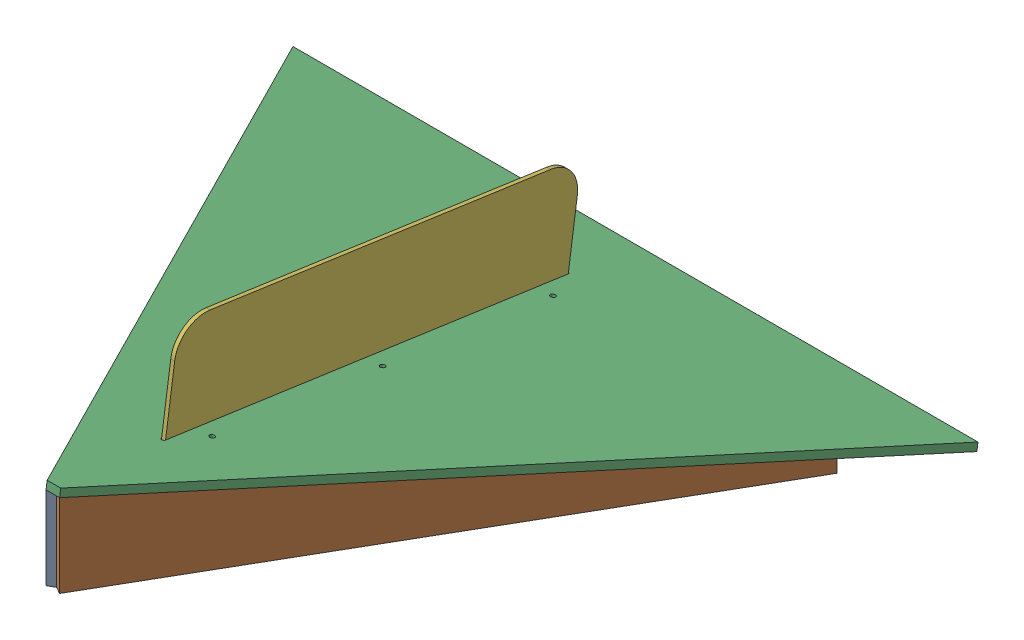
SolidWorks assembly GE-16139_ASM, configuration Default. Lengths in mm.
Overall size (1112.3 310.16 946.07).
7 component instances, 6 part files, 0 mates.
Components (placement in the parent):
- GE-16189_ASM-1: GE-16189_ASM [Default] at origin size (1112.3 147.28 946.07)
  - GE-16189-02-1: GE-16189-02 [Default] at origin size (473.08 134.72 806.69)
  - GE-16189-03-1: GE-16189-03 [Default] at (473.075 0 -3402.4927) x (-1 0 0) z (0 0 -1) size (473.08 134.72 806.69)
  - GE-16189-01-1: GE-16189-01 [Default] at (473.0748 134.7119 -3421.6102) x (-1 0 -0.000039) z (0.000039 -0.141244 -0.989975) size (1112.27 12.7 953.75)
- GE-16145-1: GE-16145 [Default] at (476.2814 19.6123 -4228.3374) x (1 0 0.000039) z (-0.000039 0.141244 0.989975) size (50.8 50.8 609.6)
- GE-16146-1: GE-16146 [Default] at (469.9077 105.7149 -3624.8491) x (-1 0 -0.000039) z (0.000039 -0.141244 -0.989975) size (50.8 50.8 609.6)
- GE-16147-1: GE-16147 [Default] at (469.9065 59.0118 -3592.5285) x (1 0 0.000039) z (-0.000006 -0.989975 0.141244) size (6.35 660.4 219.08)
